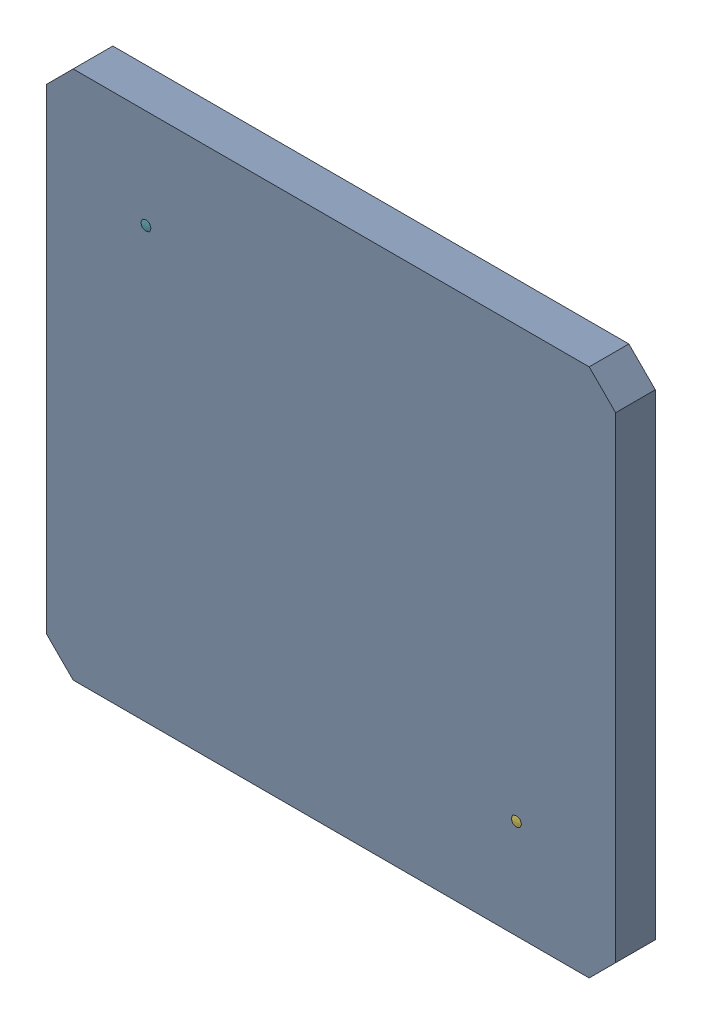
SolidWorks assembly M2, configuration Défaut. Lengths in mm.
Overall size (43 40 9.6).
8 component instances, 7 part files, 0 mates.
Components (placement in the parent):
- Open CASCADE STEP translator 6.8 1.34.1-1: Open CASCADE STEP translator 6.8 1.34.1 [Défaut] at origin size (43 40 9.6)
  - Body_1_16-1: Body_1_16 [Défaut] at origin size (43 40 3)
  - Pin_1_12-1: Pin_1_12 [Défaut] at (7.754 -9.626 0) x (0 -1 0) z (0 0 1) size (0.66 0.66 7.16)
  - Pin_2_12-1: Pin_2_12 [Défaut] at (10.294 -12.166 0) x (0 -1 0) z (0 0 1) size (0.66 0.66 7.16)
  - Pin_3_8-1: Pin_3_8 [Défaut] at (12.834 -14.706 0) x (0 -1 0) z (0 0 1) size (0.66 0.66 7.16)
  - Pin_4_6-1: Pin_4_6 [Défaut] at (15.374 -17.246 0) x (0 -1 0) z (0 0 1) size (0.66 0.66 7.16)
  - Pin_5_5-1: Pin_5_5 [Défaut] at (53 3 0) x (0 -1 0) z (0 0 1) size (3.1 3.1 9.6)
  - Pin_6_5-1: Pin_6_5 [Défaut] x (0 -1 0) z (0 0 1) size (3.1 3.1 9.6)
